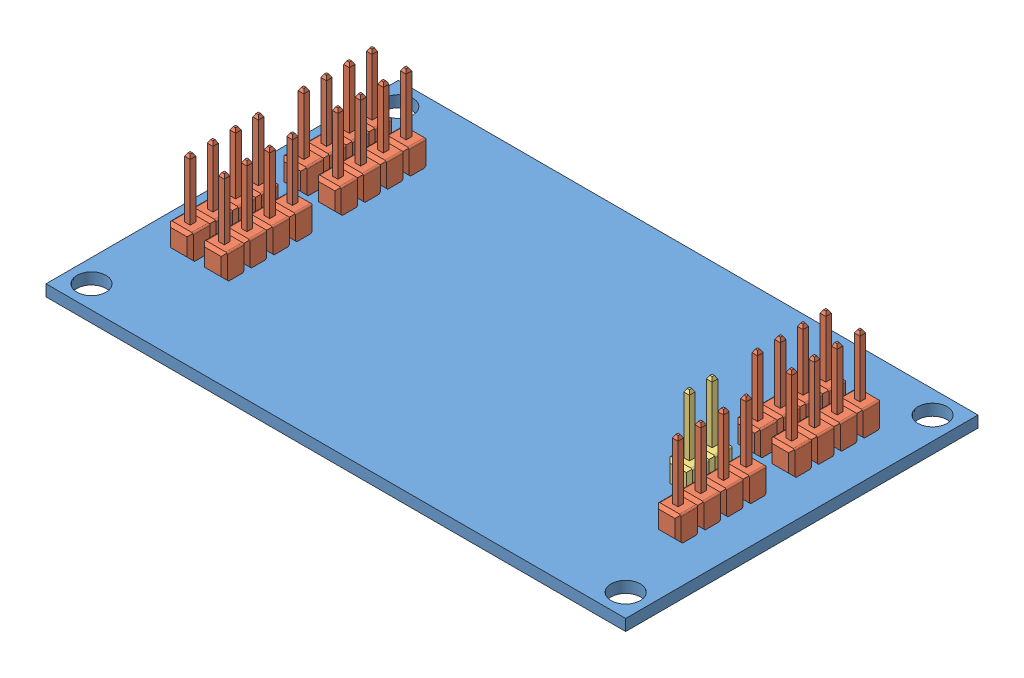
SolidWorks assembly Logic Shifter Board w components, configuration Default. Lengths in mm.
Overall size (64.77 12.7 39.37).
9 component instances, 3 part files, 24 mates.
Components (placement in the parent):
- logic shifter board-1: logic shifter board [Default] at (-7.7029 -4.2651 6.531) size (64.77 1.27 39.37)
- Pin Header 1x4 TH Pitch 2.54mm-1: Pin Header 1x4 TH Pitch 2.54mm [Default] at (-35.2196 -2.9965 -5.3447) x (0 0 1) z (0 1 0) size (10.16 2.54 12.7)
- Pin Header 1x4 TH Pitch 2.54mm-2: Pin Header 1x4 TH Pitch 2.54mm [Default] at (-35.2196 -2.9965 7.3553) x (0 0 1) z (0 1 0) size (10.16 2.54 12.7)
- Pin Header 1x4 TH Pitch 2.54mm-3: Pin Header 1x4 TH Pitch 2.54mm [Default] at (-31.4096 -2.9965 7.3553) x (0 0 1) z (0 1 0) size (10.16 2.54 12.7)
- Pin Header 1x4 TH Pitch 2.54mm-4: Pin Header 1x4 TH Pitch 2.54mm [Default] at (-31.4096 -2.9965 -5.3447) x (0 0 1) z (0 1 0) size (10.16 2.54 12.7)
- Pin Header 1x4 TH Pitch 2.54mm-5: Pin Header 1x4 TH Pitch 2.54mm [Default] at (19.2941 -2.9965 -5.3447) x (0 0 1) z (0 1 0) size (10.16 2.54 12.7)
- Pin Header 1x4 TH Pitch 2.54mm-6: Pin Header 1x4 TH Pitch 2.54mm [Default] at (15.4841 -2.9965 -5.3447) x (0 0 1) z (0 1 0) size (10.16 2.54 12.7)
- Pin Header 1x4 TH Pitch 2.54mm-7: Pin Header 1x4 TH Pitch 2.54mm [Default] at (19.2941 -2.9965 7.3553) x (0 0 1) z (0 1 0) size (10.16 2.54 12.7)
- Pin Header 1x2 TH Pitch 2.54mm-1: Pin Header 1x2 TH Pitch 2.54mm [Default] at (15.4841 -2.9965 7.3553) x (0 0 1) z (0 1 0) size (5.08 2.54 12.7)
Mates (geometry in assembly coordinates):
- Coincident1: coincident anti-aligned: plane of logic shifter board-1 through (-7.7029 -2.9951 6.531) normal (0 1 0); plane of Pin Header 1x4 TH Pitch 2.54mm-1 through (-33.9396 -2.9951 -6.1418) normal (0 -1 0)
- Concentric1: concentric aligned: cylinder of logic shifter board-1 through (-35.2196 -4.2651 -5.3447) axis (0 1 0) radius 0.5715; circle of Pin Header 1x4 TH Pitch 2.54mm-1
- Parallel1: parallel aligned: plane of logic shifter board-1 through (-40.0879 -2.9951 26.216) normal (-1 0 0); plane of Pin Header 1x4 TH Pitch 2.54mm-1 through (-36.4896 -3.0231 -6.2877) normal (-1 0 0)
- Coincident3: coincident anti-aligned: plane of logic shifter board-1 through (-7.7029 -2.9951 6.531) normal (0 1 0); plane of Pin Header 1x4 TH Pitch 2.54mm-4 through (-30.1296 -2.9951 1.4782) normal (0 -1 0)
- Coincident4: coincident anti-aligned: plane of logic shifter board-1 through (-7.7029 -2.9951 6.531) normal (0 1 0); plane of Pin Header 1x4 TH Pitch 2.54mm-3 through (-30.1296 -2.9951 6.5582) normal (0 -1 0)
- Coincident5: coincident anti-aligned: plane of logic shifter board-1 through (-7.7029 -2.9951 6.531) normal (0 1 0); plane of Pin Header 1x4 TH Pitch 2.54mm-2 through (-33.9396 -2.9951 6.5582) normal (0 -1 0)
- Coincident6: coincident anti-aligned: plane of logic shifter board-1 through (-7.7029 -2.9951 6.531) normal (0 1 0); plane of Pin Header 1x4 TH Pitch 2.54mm-5 through (20.5741 -2.9951 1.4782) normal (0 -1 0)
- Coincident7: coincident anti-aligned: plane of logic shifter board-1 through (-7.7029 -2.9951 6.531) normal (0 1 0); plane of Pin Header 1x4 TH Pitch 2.54mm-6 through (16.7641 -2.9951 -1.0618) normal (0 -1 0)
- Coincident8: coincident anti-aligned: plane of logic shifter board-1 through (-7.7029 -2.9951 6.531) normal (0 1 0); plane of Pin Header 1x4 TH Pitch 2.54mm-7 through (26.1171 -2.9951 6.0753) normal (0 -1 0)
- Concentric2: concentric aligned: circle of logic shifter board-1; circle of Pin Header 1x4 TH Pitch 2.54mm-4
- Concentric3: concentric aligned: cylinder of logic shifter board-1 through (-35.2196 -4.2651 7.3553) axis (0 1 0) radius 0.5715; circle of Pin Header 1x4 TH Pitch 2.54mm-2
- Concentric4: concentric aligned: cylinder of logic shifter board-1 through (-31.4096 -4.2651 7.3553) axis (0 1 0) radius 0.5715; circle of Pin Header 1x4 TH Pitch 2.54mm-3
- Concentric5: concentric aligned: cylinder of logic shifter board-1 through (15.4841 -4.2651 -5.3447) axis (0 1 0) radius 0.5715; circle of Pin Header 1x4 TH Pitch 2.54mm-6
- Concentric6: concentric aligned: cylinder of logic shifter board-1 through (19.2941 -4.2651 -5.3447) axis (0 1 0) radius 0.5715; circle of Pin Header 1x4 TH Pitch 2.54mm-5
- Concentric7: concentric aligned: cylinder of logic shifter board-1 through (19.2941 -4.2651 7.3553) axis (0 1 0) radius 0.5715; circle of Pin Header 1x4 TH Pitch 2.54mm-7
- Coincident9: coincident anti-aligned: plane of logic shifter board-1 through (-7.7029 -2.9951 6.531) normal (0 1 0); plane of Pin Header 1x2 TH Pitch 2.54mm-1 through (16.7641 -2.9951 6.5582) normal (0 -1 0)
- Concentric8: concentric aligned: cylinder of logic shifter board-1 through (15.4841 -4.2651 7.3553) axis (0 1 0) radius 0.5715; circle of Pin Header 1x2 TH Pitch 2.54mm-1
- Parallel2: parallel aligned: plane of logic shifter board-1 through (-40.0879 -2.9951 26.216) normal (-1 0 0); plane of Pin Header 1x4 TH Pitch 2.54mm-2 through (-36.4896 -3.0231 6.4123) normal (-1 0 0)
- Parallel3: parallel aligned: plane of logic shifter board-1 through (-40.0879 -2.9951 26.216) normal (-1 0 0); plane of Pin Header 1x4 TH Pitch 2.54mm-3 through (-32.6796 -3.0231 6.4123) normal (-1 0 0)
- Parallel4: parallel aligned: plane of logic shifter board-1 through (-40.0879 -2.9951 26.216) normal (-1 0 0); plane of Pin Header 1x4 TH Pitch 2.54mm-4 through (-32.6796 -3.0231 -6.2877) normal (-1 0 0)
- Parallel5: parallel aligned: plane of logic shifter board-1 through (-40.0879 -2.9951 26.216) normal (-1 0 0); plane of Pin Header 1x4 TH Pitch 2.54mm-6 through (14.2141 -3.0231 -6.2877) normal (-1 0 0)
- Parallel6: parallel anti-aligned: plane of logic shifter board-1 through (-40.0879 -2.9951 26.216) normal (-1 0 0); plane of Pin Header 1x4 TH Pitch 2.54mm-5 through (20.5641 -3.0231 -6.2877) normal (1 0 0)
- Parallel7: parallel anti-aligned: plane of logic shifter board-1 through (-40.0879 -2.9951 26.216) normal (-1 0 0); plane of Pin Header 1x2 TH Pitch 2.54mm-1 through (16.7541 -3.0231 6.4123) normal (1 0 0)
- Parallel8: parallel: plane of logic shifter board-1 through (-40.0879 -2.9951 26.216) normal (-1 0 0); line of Pin Header 1x4 TH Pitch 2.54mm-7 through (20.5641 -0.3693 8.2798) axis (0 0 -1)
